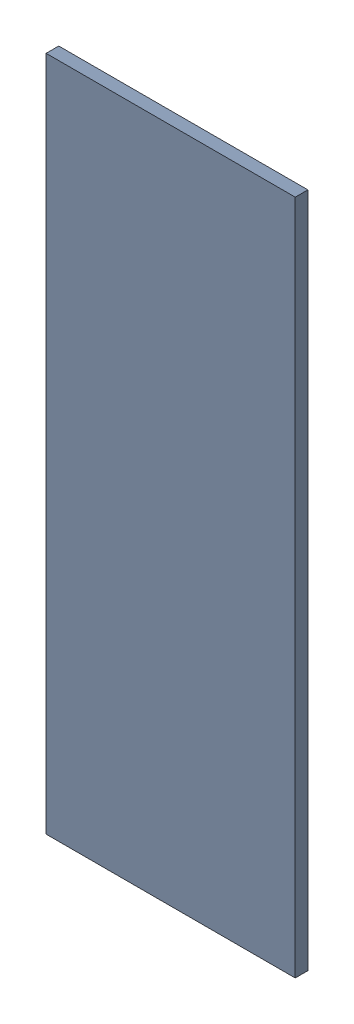
SolidWorks assembly Pad RAK4600-39(21.225mm,31.391mm) on Top Layer, configuration Predeterminado. Lengths in mm.
Overall size (0.7 1.9 0.04).
2 component instances, 1 part files, 0 mates.
Components (placement in the parent):
- Pad RAK4600-39(21.225mm,31.391mm) on Top Layer-1-1: Pad RAK4600-39(21.225mm,31.391mm) on Top Layer-1 [Predeterminado] at (-68.317 -44.187 -0.0457) size (0.7 1.9 0.04)
  - Pad RAK4600-39(21.225mm,31.391mm) on Top Layer-Part-1-1: Pad RAK4600-39(21.225mm,31.391mm) on Top Layer-Part-1 [Predeterminado] at origin size (0.7 1.9 0.04)
